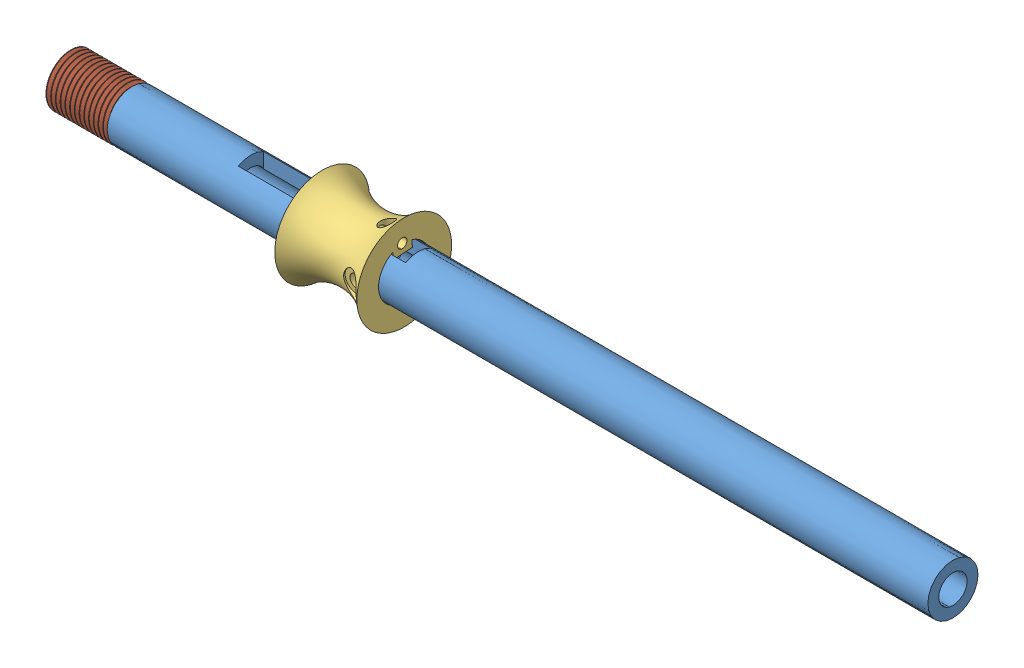
SolidWorks assembly slider assembly v-6 23-Nov-2017, configuration Default. Lengths in mm.
Overall size (140.35 16.12 16.1).
4 component instances, 3 part files, 1 mates.
Components (placement in the parent):
- slider handle assembly v-5 22-Nov-2017-1: slider handle assembly v-5 22-Nov-2017 [Default] at (-2.8853 21.3407 35.0574) size (140.35 13 13)
  - wheel_handle_body_slider v-4 06-Nov-2017-1: wheel_handle_body_slider v-4 06-Nov-2017 [Default] at (-10.0168 48.9172 77.5775) size (130 7.94 7.94)
  - M8X0.75-1: M8X0.75 [91290A414] at (-10.0168 48.9172 77.5775) x (0 0 -1) z (1 0 0) size (13 13 10.51)
- slider v-7 23-Nov-2017-1: slider v-7 23-Nov-2017 [Default] at (23.9396 70.6298 112.6634) x (1 0 0) z (0 -0.076475 0.997071) size (13.21 15.01 15)
Mates (geometry in assembly coordinates):
- Concentric1: concentric anti-aligned: circle of slider handle assembly v-5 22-Nov-2017-1/wheel_handle_body_slider v-4 06-Nov-2017-1; circle of slider v-7 23-Nov-2017-1
